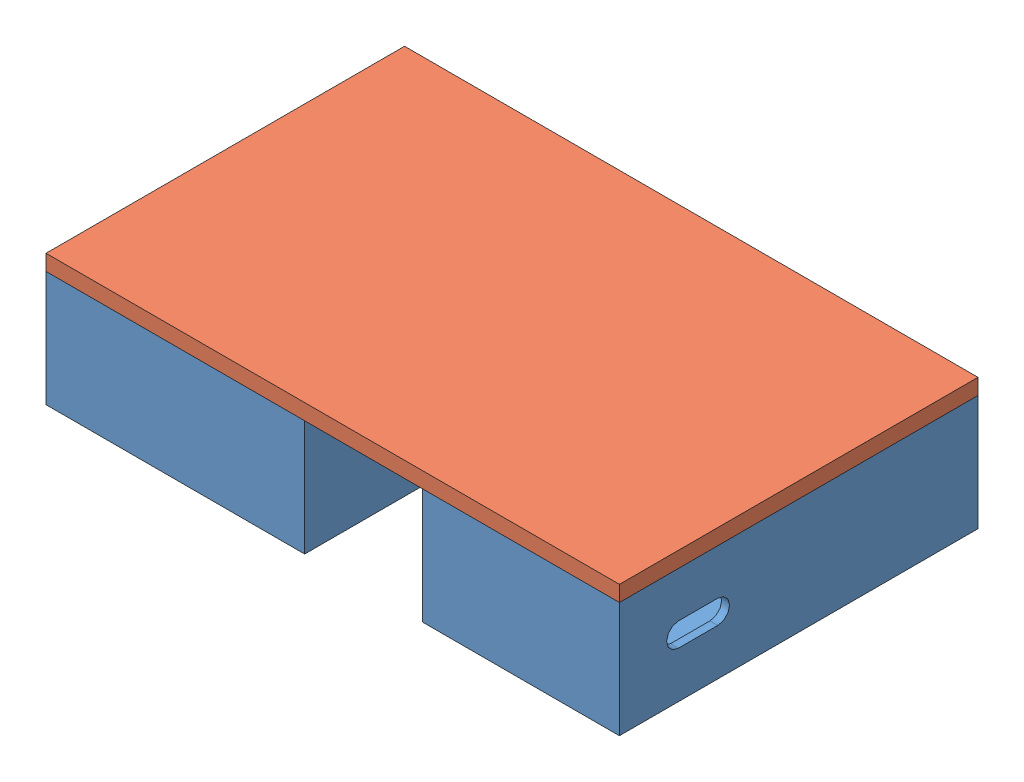
SolidWorks assembly Counter Box, configuration Default. Lengths in mm.
Overall size (185.4 42.9 116.03).
2 component instances, 2 part files, 6 mates.
Components (placement in the parent):
- Counter Base-1: Counter Base [Default] at origin size (185.11 37.82 115.76)
- Counter Lid-1: Counter Lid [Default] at (185.3971 42.6199 0.2794) x (-1 0 0) z (0 0 1) size (185.12 12.7 115.75)
Mates (geometry in assembly coordinates):
- Symmetric1: symmetric aligned: plane of Counter Base-1 through (0 37.5399 0) normal (0 1 0); plane of Counter Lid-1 through (185.3971 37.5399 0.2794) normal (0 -1 0); plane of Counter Lid-1 through (185.3971 37.5399 0.2794) normal (0 -1 0)
- Coincident4: coincident anti-aligned: plane of Counter Base-1 through (0 37.5399 0) normal (0 1 0); plane of Counter Lid-1 through (185.3971 37.5399 0.2794) normal (0 -1 0)
- Parallel3: parallel aligned: line of Counter Base-1 through (185.105 37.5399 0) axis (0 0 -1); line of Counter Lid-1 through (185.3971 42.6199 0.2794) axis (0 0 -1)
- Parallel4: parallel anti-aligned: line of Counter Base-1 through (83.505 0 37.5399) axis (0 1 0); line of Counter Lid-1 through (185.3971 42.6199 0.2794) axis (-1 0 0)
- Coincident5: coincident anti-aligned: plane of Counter Base-1 through (124.145 37.5399 -2.54) normal (0 0 -1); plane of Counter Lid-1 through (124.653 29.9199 -2.54) normal (0 0 1)
- Coincident6: coincident anti-aligned: plane of Counter Base-1 through (182.565 37.5399 -113.2154) normal (-1 0 0); plane of Counter Lid-1 through (182.565 29.9199 -112.649) normal (1 0 0)
